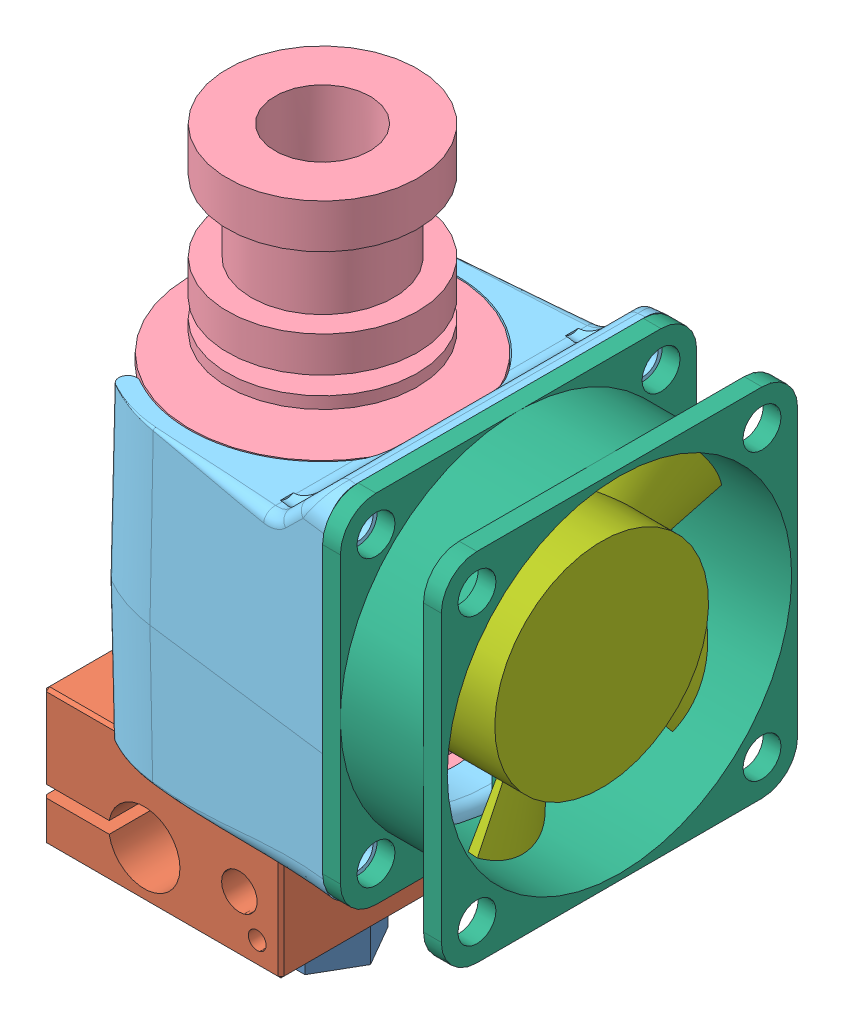
SolidWorks assembly e3d v6, configuration Default. Lengths in mm.
Overall size (40.5 61.3 39.45).
9 component instances, 7 part files, 12 mates.
Components (placement in the parent):
- e3d nozzle (0.4)-1: e3d nozzle (0.4) [Default] at (0 -4.25 0) size (8.08 12.5 7)
- e3d heaterblock-2: e3d heaterblock [Default] at (-5.5 -1.25 0) size (20 11.5 16)
- e3d heat break-2: e3d heat break [Default] at (0 5.25 0) size (7 21.9 7)
- e3d heatsink-2: e3d heatsink [Default] at (0 12.35 0) x (0.978214 0 -0.207597) z (0.207597 0 0.978214) size (22.3 42.7 22.3)
- fanduct-2: fanduct [Default] at (6.8279 9.7284 26.4875) x (-1 0 0) z (0 0 -1) size (32 39.46 39.45)
  - fan duct-1: fan duct [Default] at (6.8279 2.6216 26.4875) size (22.41 30.18 30)
  - fan-1: fan [Default] at (15.7816 1.6787 26.8895) x (0 0 1) z (-1 0 0) size (39.45 39.46 10)
    - fan sub1-1: fan sub1 [Default] at (-0.402 15.9429 23.9537) size (30 30 10)
    - fan sub2-1: fan sub2 [Default] at (-0.402 15.9429 33.9537) x (0 0 1) z (-0.65899 0.752151 0) size (8.5 27.91 28)
Mates (geometry in assembly coordinates):
- Symmetric1: symmetric aligned: plane of e3d nozzle (0.4)-1 through (-2.0207 -1.25 -3.5) normal (0 0 -1); plane of e3d nozzle (0.4)-1 through (2.0207 -1.25 3.5) normal (0 0 1); plane of assembly through (0 0 0) normal (0 0 1)
- Symmetric2: symmetric aligned: line of e3d nozzle (0.4)-1 through (3 4.0415 -1.25) axis (0 0 -1); line of e3d nozzle (0.4)-1 through (3 -4.0415 -1.25) axis (0 0 -1); plane of assembly
- Symmetric3: symmetric aligned: plane of e3d nozzle (0.4)-1 through (0 6.25 0) normal (0 1 0); plane of e3d nozzle (0.4)-1 through (0 -6.25 0) normal (0 -1 0); plane of assembly through (0 0 0) normal (0 1 0)
- Concentric2: concentric anti-aligned: cylinder of e3d nozzle (0.4)-1 through (0 -1.25 0) axis (0 1 0) radius 3; cylinder of e3d heaterblock-2 through (0 -1.25 0) axis (0 -1 0) radius 3
- Coincident3: coincident anti-aligned: plane of e3d nozzle (0.4)-1 through (0 -1.25 0) normal (0 1 0); plane of e3d heaterblock-2 through (-5.5 -1.25 0) normal (0 -1 0)
- Concentric3: concentric anti-aligned: cylinder of e3d heaterblock-2 through (0 -1.25 0) axis (0 -1 0) radius 3; cylinder of e3d heat break-2 through (0 5.25 0) axis (0 1 0) radius 3
- Coincident4: coincident aligned: plane of e3d heaterblock-2 through (-5.5 10.25 0) normal (0 1 0); plane of e3d heat break-2 through (1.4 10.25 0) normal (0 1 0)
- Concentric4: concentric anti-aligned: cylinder of e3d heat break-2 through (0 5.25 0) axis (0 1 0) radius 3.5; cylinder of e3d heatsink-2 through (0 55.05 0) axis (0 -1 0) radius 3.5
- Coincident5: coincident aligned: plane of e3d heat break-2 through (3.5 12.35 0) normal (0 -1 0); plane of e3d heatsink-2 through (3.4238 12.35 -0.7266) normal (0 -1 0)
- Concentric5: concentric aligned: cylinder of e3d heatsink-2 through (0 55.05 0) axis (0 -1 0) radius 11.15; cone of fanduct-2/fan duct-1 through (0 39.714 0) axis (0 -1 0)
- Coincident6: coincident aligned: plane of e3d heatsink-2 through (10.9071 38.35 -2.3147) normal (0 1 0); plane of fanduct-2/fan duct-1 through (6.951 38.35 0) normal (0 1 0)
- Parallel1: parallel aligned: plane of e3d heaterblock-2 through (4.5 10.25 8) normal (0 0 1); plane of fanduct-2/fan-1/fan sub1-1 through (15 42.35 15) normal (0 0 1)
